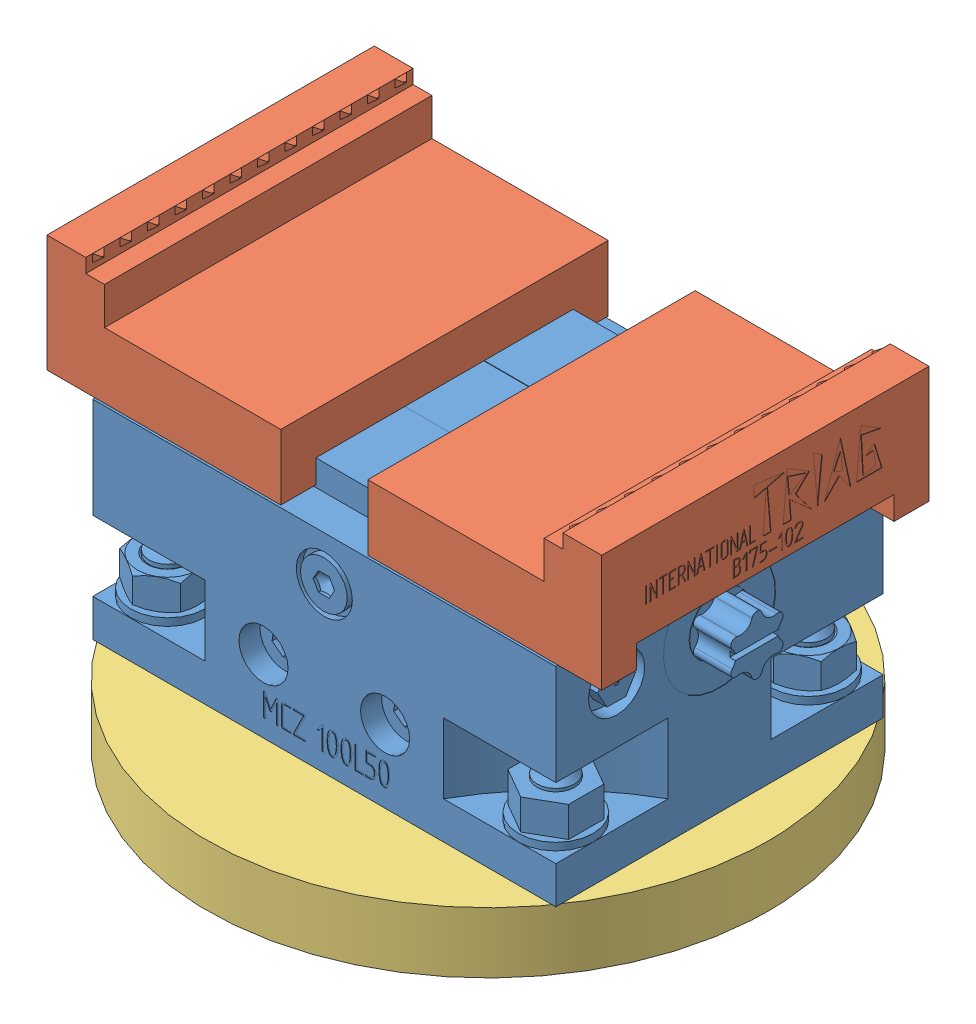
SolidWorks assembly ETAU 82-102mm, configuration Défaut. Lengths in mm.
Overall size (120 83 120).
4 component instances, 3 part files, 11 mates.
Components (placement in the parent):
- Copie de MCZ 100L50_KS^ETAU 82-102mm-1: Copie de MCZ 100L50_KS^ETAU 82-102mm [Défaut] at (0 0 30) size (107 62 70.1) (virtual)
- Copie de B175-102_KS^ETAU 82-102mm-1: Copie de B175-102_KS^ETAU 82-102mm [Défaut] at (41.55 43.436 0) x (0 0 -1) z (0 1 0) size (70 50 25) (virtual)
- Copie de B175-102_KS^ETAU 82-102mm-2: Copie de B175-102_KS^ETAU 82-102mm [Défaut] at (-41.55 43.436 0) x (0 0 1) z (0 1 0) size (70 50 25) (virtual)
- Copie de BASE ADAPT^ETAU 82-102mm-1: Copie de BASE ADAPT^ETAU 82-102mm [Défaut] at (0 -37.064 0) x (1 0 0) z (0 1 0) size (120 120 13) (virtual)
Mates (geometry in assembly coordinates):
- Coïncidente1: coincident aligned: plane of Copie de MCZ 100L50_KS^ETAU 82-102mm-1 through (0 0 30) normal (1 0 0); plane of assembly through (0 0 0) normal (1 0 0)
- Coïncidente3: coincident aligned: plane of Copie de MCZ 100L50_KS^ETAU 82-102mm-1 through (0 0 0) normal (0 0 1); plane of assembly through (0 0 0) normal (0 0 1)
- Coïncidente4: coincident aligned: plane of Copie de MCZ 100L50_KS^ETAU 82-102mm-1 through (0 0 30) normal (0 1 0); plane of assembly through (0 0 0) normal (0 1 0)
- Coïncidente5: coincident anti-aligned: plane of Copie de B175-102_KS^ETAU 82-102mm-1 through (41.55 43.436 0) normal (0 0 -1); plane of assembly through (0 0 0) normal (0 0 1)
- Coïncidente6: coincident aligned: plane of Copie de B175-102_KS^ETAU 82-102mm-2 through (-41.55 43.436 0) normal (0 0 1); plane of assembly through (0 0 0) normal (0 0 1)
- Coïncidente7: coincident anti-aligned: plane of Copie de MCZ 100L50_KS^ETAU 82-102mm-1 through (49 25.936 0) normal (0 1 0); plane of Copie de B175-102_KS^ETAU 82-102mm-2 through (-43.6 25.936 -18.15) normal (0 -1 0)
- Coïncidente9: coincident anti-aligned: plane of Copie de MCZ 100L50_KS^ETAU 82-102mm-1 through (49 25.936 0) normal (0 1 0); plane of Copie de B175-102_KS^ETAU 82-102mm-1 through (43.6 25.936 18.15) normal (0 -1 0)
- Symétrique1: symmetric aligned: plane of Copie de MCZ 100L50_KS^ETAU 82-102mm-1 through (0 0 30) normal (1 0 0); plane of Copie de B175-102_KS^ETAU 82-102mm-2 through (-51 46.086 -38.5) normal (1 0 0); plane of Copie de B175-102_KS^ETAU 82-102mm-1 through (51 46.086 38.5) normal (-1 0 0)
- Distance1: distance = 102 mm anti-aligned: plane of Copie de B175-102_KS^ETAU 82-102mm-1 through (51 46.086 38.5) normal (-1 0 0); plane of Copie de B175-102_KS^ETAU 82-102mm-2 through (-51 46.086 -38.5) normal (1 0 0)
- Coïncidente10: coincident anti-aligned: plane of Copie de MCZ 100L50_KS^ETAU 82-102mm-1 through (10 -24.064 0) normal (0 -1 0); plane of Copie de BASE ADAPT^ETAU 82-102mm-1 through (0 -24.064 0) normal (0 1 0)
- Coaxiale1: concentric aligned: cylinder of Copie de MCZ 100L50_KS^ETAU 82-102mm-1 through (0 -22.064 0) axis (0 -1 0) radius 11.7378; cylinder of Copie de BASE ADAPT^ETAU 82-102mm-1 through (0 -24.064 0) axis (0 -1 0) radius 60
